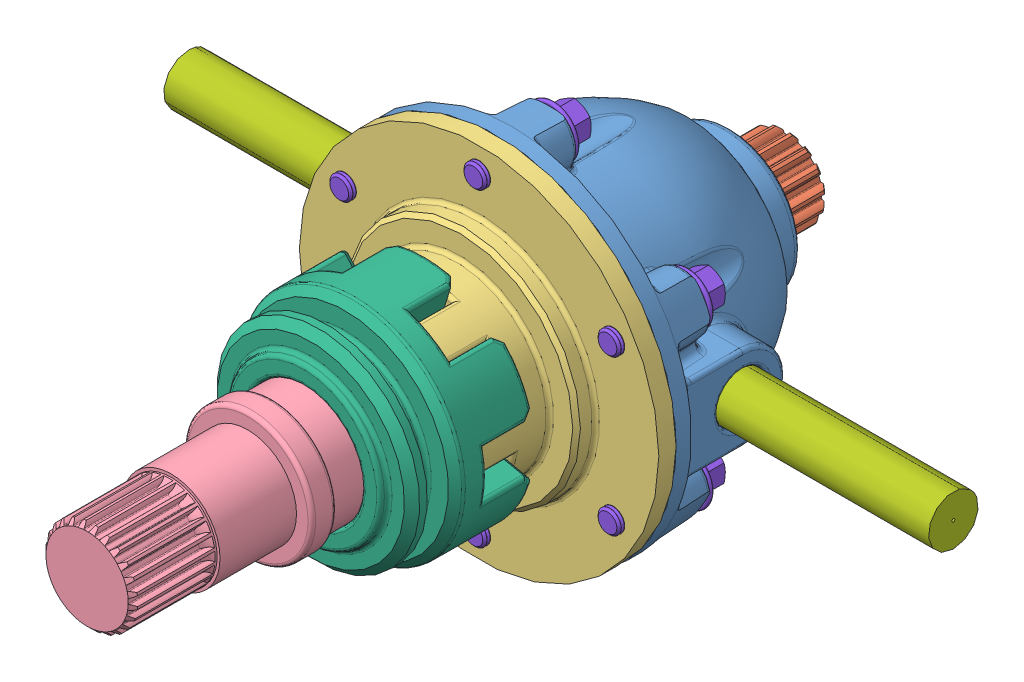
SolidWorks assembly Differential Gear Box, configuration Default. Lengths in mm.
Overall size (200 94.6 183.35).
14 component instances, 8 part files, 32 mates.
Components (placement in the parent):
- 01. Cover 01-1: 01. Cover 01 [Default] at (30.8489 71.5793 89.8367) x (0 0 -1) z (-1 0 0) size (61.5 94 94)
- 06. Gear 02-1: 06. Gear 02 [Default] at (37.026 90.2552 75.6697) x (0 0 1) z (-0.635651 -0.771977 0) size (47.63 40.95 40.95)
- 02. Cover 02-1: 02. Cover 02 [Default] at (30.8489 71.5793 86.3367) x (0 0 1) z (-1 0 0) size (36 94 94)
- 03. Shaft-1: 03. Shaft [Default] at (30.8489 71.5793 196.8367) x (0 0 -1) z (-0.69192 -0.721974 0) size (116.5 33.5 33.5)
- 05. Gear 01-1: 05. Gear 01 [Default] at (24.1376 53.0887 65.0036) x (0 0 -1) z (-0.021252 0.999774 0) size (10.63 40.95 40.95)
- 04. Joint-1: 04. Joint [Default] at (30.8489 71.5793 121.3367) x (-0.5 -0.866025 0) z (0.866025 -0.5 0) size (58 32.06 58)
- straight bevel gear_iso-1: straight bevel gear_iso [ISO - Straight bevel gear 1M 30GT 40PT 20PA 8FW ---30O13H100MD0.8N] at (10.2255 71.5793 70.3367) x (1 0 0) z (0 0.962023 -0.27297) size (87.36 32.09 32.25)
- straight bevel gear_iso-2: straight bevel gear_iso [ISO - Straight bevel gear 1M 30GT 40PT 20PA 8FW ---30O13H100MD0.8N] at (51.4723 71.5793 70.3367) x (-1 0 0) z (0 0.560044 -0.828463) size (87.36 32.09 32.25)
- hex flange bolt small_iso-1: hex flange bolt small_iso [ISO 4162 - M6 x 20 x 20-S] at (-4.2252 91.8293 69.0367) x (0 0 1) z (-1 0 0) size (26.8 13.6 13.6)
- hex flange bolt small_iso-2: hex flange bolt small_iso [ISO 4162 - M6 x 20 x 20-S] at (30.8489 112.0793 69.0367) x (0 0 1) z (-1 0 0) size (26.8 13.6 13.6)
- hex flange bolt small_iso-3: hex flange bolt small_iso [ISO 4162 - M6 x 20 x 20-S] at (65.9229 91.8293 69.0367) x (0 0 1) z (-1 0 0) size (26.8 13.6 13.6)
- hex flange bolt small_iso-4: hex flange bolt small_iso [ISO 4162 - M6 x 20 x 20-S] at (-4.2252 51.3293 69.0367) x (0 0 1) z (-1 0 0) size (26.8 13.6 13.6)
- hex flange bolt small_iso-6: hex flange bolt small_iso [ISO 4162 - M6 x 20 x 20-S] at (65.9229 51.3293 69.0367) x (0 0 1) z (-1 0 0) size (26.8 13.6 13.6)
- hex flange bolt small_iso-7: hex flange bolt small_iso [ISO 4162 - M6 x 20 x 20-S] at (30.8489 31.0793 69.0367) x (0 0 1) z (-1 0 0) size (26.8 13.6 13.6)
Mates (geometry in assembly coordinates):
- Concentric1: concentric anti-aligned: cylinder of 01. Cover 01-1 through (30.8489 71.5793 89.8367) axis (0 0 -1) radius 18.5; cylinder of 06. Gear 02-1 through (30.8489 71.5793 50.4819) axis (0 0 1) radius 14
- Concentric2: concentric anti-aligned: cylinder of 01. Cover 01-1 through (30.8489 71.5793 89.8367) axis (0 0 1) radius 47; cylinder of 02. Cover 02-1 through (30.8489 71.5793 86.3367) axis (0 0 -1) radius 47
- Concentric3: concentric anti-aligned: cylinder of 01. Cover 01-1 through (65.9229 51.3293 89.8367) axis (0 0 -1) radius 3; cylinder of 02. Cover 02-1 through (65.9229 51.3293 81.3367) axis (0 0 1) radius 3
- Concentric4: concentric anti-aligned: cylinder of 03. Shaft-1 through (30.8489 71.5793 196.8367) axis (0 0 1) radius 15.25; cylinder of 05. Gear 01-1 through (30.8489 71.5793 90.1914) axis (0 0 -1) radius 14
- Concentric5: concentric aligned: cylinder of 03. Shaft-1 through (37.3905 80.1098 101.8367) axis (0 0 -1) radius 3.2; cylinder of 05. Gear 01-1 through (37.3905 80.1098 98.3367) axis (0 0 -1) radius 3.2
- Distance1: distance = 1 mm aligned: plane of 03. Shaft-1 through (39.5126 63.2763 80.3367) normal (0 0 -1); plane of 05. Gear 01-1 through (30.8489 71.5793 81.3367) normal (0 0 -1)
- Concentric6: concentric anti-aligned: cylinder of 02. Cover 02-1 through (30.8489 71.5793 86.3367) axis (0 0 -1) radius 23.5; cylinder of 03. Shaft-1 through (30.8489 71.5793 196.8367) axis (0 0 1) radius 15.25
- Concentric7: concentric aligned: cylinder of 02. Cover 02-1 through (30.8489 71.5793 86.3367) axis (0 0 -1) radius 23.5; cylinder of 04. Joint-1 through (30.8489 71.5793 121.3367) axis (0 0 -1) radius 29
- Coincident2: coincident aligned: plane of 02. Cover 02-1 through (25.6973 87.78 108.3367) normal (0.952979 0.303035 0); plane of 04. Joint-1 through (39.6369 43.9429 108.3367) normal (0.952979 0.303035 0)
- Coincident3: coincident anti-aligned: plane of 02. Cover 02-1 through (30.8489 71.5793 108.3367) normal (0 0 1); plane of 04. Joint-1 through (30.8489 71.5793 108.3367) normal (0 0 -1)
- Concentric8: concentric aligned: cylinder of 01. Cover 01-1 through (-16.1531 71.5793 70.3367) axis (1 0 0) radius 6.5; cylinder of straight bevel gear_iso-1 through (-69.1512 71.5793 70.3367) axis (1 0 0) radius 6.5
- Coincident4: coincident: point of 01. Cover 01-1; unknown of ?
- GearMate1: gear = 30 : 40 mm: circle of 06. Gear 02-1; circle of straight bevel gear_iso-1
- Concentric9: concentric anti-aligned: cylinder of straight bevel gear_iso-1 through (-69.1512 71.5793 70.3367) axis (1 0 0) radius 6.5; cylinder of straight bevel gear_iso-2 through (130.849 71.5793 70.3367) axis (-1 0 0) radius 6.5
- Coincident5: coincident: point of straight bevel gear_iso-1; point of straight bevel gear_iso-2
- GearMate2: gear = 30 : 40 mm: circle of 06. Gear 02-1; circle of straight bevel gear_iso-2
- Distance3: distance = 11 mm: plane of 06. Gear 02-1 through (30.8489 71.5793 59.3367) normal (0 0 1); line of straight bevel gear_iso-1 through (0.2255 71.5793 70.3367) axis (1 0 0)
- Distance4: distance = 11 mm: line of straight bevel gear_iso-1 through (0.2255 71.5793 70.3367) axis (1 0 0); plane of 05. Gear 01-1 through (30.8489 71.5793 81.3367) normal (0 0 -1)
- GearMate3: gear = 30 : 40 mm: circle of 05. Gear 01-1; circle of straight bevel gear_iso-1
- Coincident8: coincident anti-aligned: plane of 01. Cover 01-1 through (30.8489 24.5793 89.8367) normal (0 0 1); plane of 02. Cover 02-1 through (30.8489 105.5793 89.8367) normal (0 0 -1)
- Concentric12: concentric aligned: cylinder of 01. Cover 01-1 through (-4.2252 91.8293 89.8367) axis (0 0 -1) radius 3; cylinder of hex flange bolt small_iso-1 through (-4.2252 91.8293 69.0367) axis (0 0 -1) radius 3
- Coincident9: coincident anti-aligned: plane of 01. Cover 01-1 through (30.8489 71.5793 75.8367) normal (0 0 -1); plane of hex flange bolt small_iso-1 through (-4.2252 96.4481 75.8367) normal (0 0 1)
- Concentric13: concentric aligned: cylinder of 01. Cover 01-1 through (30.8489 112.0793 89.8367) axis (0 0 -1) radius 3; cylinder of hex flange bolt small_iso-2 through (30.8489 112.0793 69.0367) axis (0 0 -1) radius 3
- Coincident10: coincident anti-aligned: plane of 01. Cover 01-1 through (30.8489 71.5793 75.8367) normal (0 0 -1); plane of hex flange bolt small_iso-2 through (30.8489 116.6981 75.8367) normal (0 0 1)
- Concentric14: concentric aligned: cylinder of 01. Cover 01-1 through (65.9229 91.8293 89.8367) axis (0 0 -1) radius 3; cylinder of hex flange bolt small_iso-3 through (65.9229 91.8293 69.0367) axis (0 0 -1) radius 3
- Coincident11: coincident anti-aligned: plane of 01. Cover 01-1 through (30.8489 71.5793 75.8367) normal (0 0 -1); plane of hex flange bolt small_iso-3 through (65.9229 96.4481 75.8367) normal (0 0 1)
- Concentric15: concentric aligned: cylinder of 01. Cover 01-1 through (-4.2252 51.3293 89.8367) axis (0 0 -1) radius 3; cylinder of hex flange bolt small_iso-4 through (-4.2252 51.3293 69.0367) axis (0 0 -1) radius 3
- Coincident12: coincident anti-aligned: plane of 01. Cover 01-1 through (30.8489 71.5793 75.8367) normal (0 0 -1); plane of hex flange bolt small_iso-4 through (-4.2252 55.9481 75.8367) normal (0 0 1)
- Concentric17: concentric aligned: cylinder of 01. Cover 01-1 through (65.9229 51.3293 89.8367) axis (0 0 -1) radius 3; cylinder of hex flange bolt small_iso-6 through (65.9229 51.3293 69.0367) axis (0 0 -1) radius 3
- Coincident14: coincident anti-aligned: plane of 01. Cover 01-1 through (30.8489 71.5793 75.8367) normal (0 0 -1); plane of hex flange bolt small_iso-6 through (65.9229 55.9481 75.8367) normal (0 0 1)
- Concentric18: concentric aligned: cylinder of 01. Cover 01-1 through (30.8489 31.0793 89.8367) axis (0 0 -1) radius 3; cylinder of hex flange bolt small_iso-7 through (30.8489 31.0793 69.0367) axis (0 0 -1) radius 3
- Coincident15: coincident anti-aligned: plane of 01. Cover 01-1 through (30.8489 71.5793 75.8367) normal (0 0 -1); plane of hex flange bolt small_iso-7 through (30.8489 35.6981 75.8367) normal (0 0 1)
